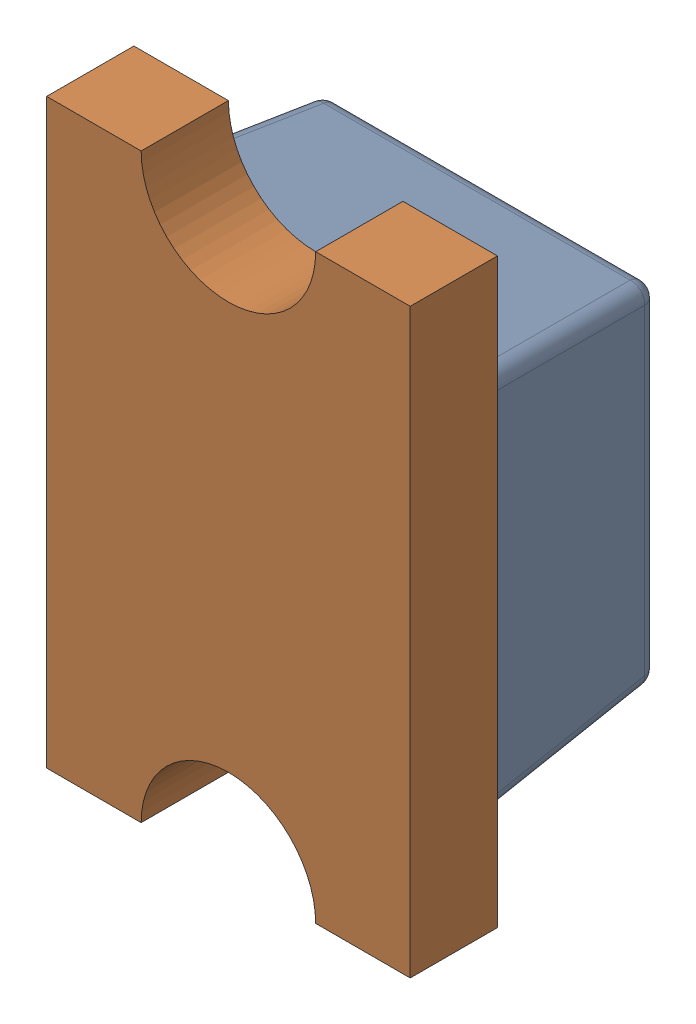
SolidWorks assembly D2_XLR4, configuration Default. Lengths in mm.
Overall size (1.25 2 0.9).
2 component instances, 2 part files, 0 mates.
Components (placement in the parent):
- LED 0805 Lens RED-1: LED 0805 Lens RED [Default] at (69.043 70.1039 -1.2114) x (0 -1 0) z (1 0 0) size (1.3 0.6 1.25)
- LED 0805 Base RED-1: LED 0805 Base RED [Default] at (69.043 70.1039 -1.2114) x (0 -1 0) z (1 0 0) size (2 0.4 1.25)
